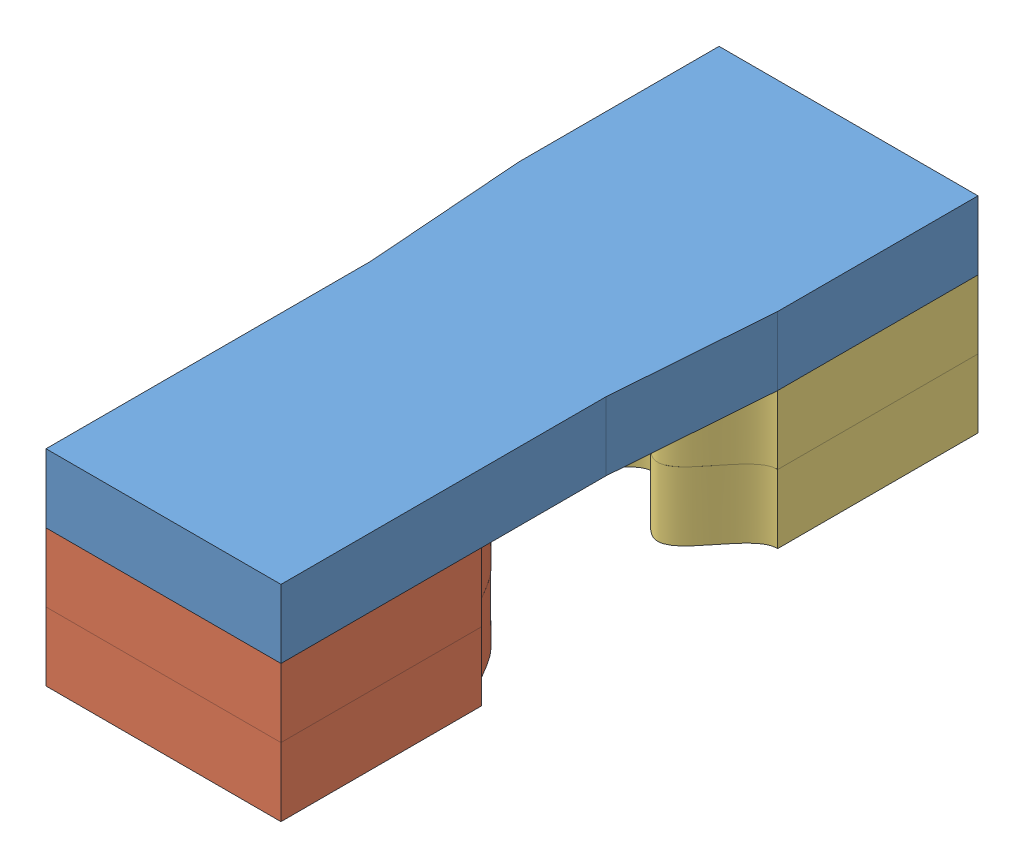
SolidWorks assembly Assem2, configuration Default. Lengths in mm.
Overall size (13.1 9 32.23).
5 component instances, 3 part files, 11 mates.
Components (placement in the parent):
- tooth-connector-1: tooth-connector [Default] at (4.0585 13.7672 27.059) size (11.34 3 30)
- tooth-inside-1: tooth-inside [Default] at (4.0589 7.7672 106.8551) x (0.992546 0 -0.121869) z (0.121869 0 0.992546) size (11.34 3.06 12.33)
- tooth-outside-1: tooth-outside [Default] at (4.0562 10.7672 101.8804) x (0.996195 0 -0.087156) z (0.087156 0 0.996195) size (12.06 3 11.83)
- tooth-inside-2: tooth-inside [Default] at (4.0589 10.7672 106.8551) x (0.992546 0 -0.121869) z (0.121869 0 0.992546) size (11.34 3.06 12.33)
- tooth-outside-2: tooth-outside [Default] at (4.0562 7.7672 101.8804) x (0.996195 0 -0.087156) z (0.087156 0 0.996195) size (12.06 3 11.83)
Mates (geometry in assembly coordinates):
- Coincident1: coincident anti-aligned: plane of tooth-inside-1 through (45.9551 10.7672 46.7695) normal (0 1 0); plane of tooth-inside-2 through (45.9551 10.7672 46.7695) normal (0 -1 0)
- Coincident2: coincident aligned: plane of tooth-inside-1 through (-6.1335 10.7672 42.059) normal (0 0 1); plane of tooth-inside-2 through (-6.1335 13.7672 42.059) normal (0 0 1)
- Coincident3: coincident aligned: plane of tooth-inside-1 through (4.1556 7.7672 33.2844) normal (1 0 0); plane of tooth-inside-2 through (4.1556 10.7672 33.2844) normal (1 0 0)
- Coincident4: coincident anti-aligned: plane of tooth-outside-1 through (56.2825 10.7672 39.6395) normal (0 -1 0); plane of tooth-outside-2 through (56.2825 10.7672 39.6395) normal (0 1 0)
- Coincident5: coincident aligned: plane of tooth-outside-1 through (9.7238 175.3943 20.8286) normal (1 0 0); plane of tooth-outside-2 through (9.7238 172.3943 20.8286) normal (1 0 0)
- Coincident6: coincident aligned: plane of tooth-outside-1 through (-1.6115 10.7672 12.059) normal (0 0 -1); plane of tooth-outside-2 through (-1.6115 7.7672 12.059) normal (0 0 -1)
- Coincident7: coincident anti-aligned: plane of tooth-connector-1 through (4.0585 13.7672 27.059) normal (0 -1 0); plane of tooth-outside-1 through (56.2825 13.7672 39.6395) normal (0 1 0)
- Coincident10: coincident aligned: plane of tooth-connector-1 through (-1.6115 16.7672 42.059) normal (-1 0 0); plane of tooth-outside-1 through (-1.6115 10.7672 20.8286) normal (-1 0 0)
- Coincident11: coincident anti-aligned: plane of tooth-connector-1 through (4.0585 13.7672 27.059) normal (0 -1 0); plane of tooth-inside-2 through (45.9551 13.7672 46.7695) normal (0 1 0)
- Coincident15: coincident aligned: plane of tooth-connector-1 through (-1.6115 16.7672 42.059) normal (0 0 1); plane of tooth-inside-2 through (-6.1335 13.7672 42.059) normal (0 0 1)
- Coincident18: coincident aligned: line of tooth-connector-1 through (9.2035 13.7672 42.059) axis (0 1 0); line of tooth-inside-2 through (9.2035 10.7672 42.059) axis (0 1 0)
